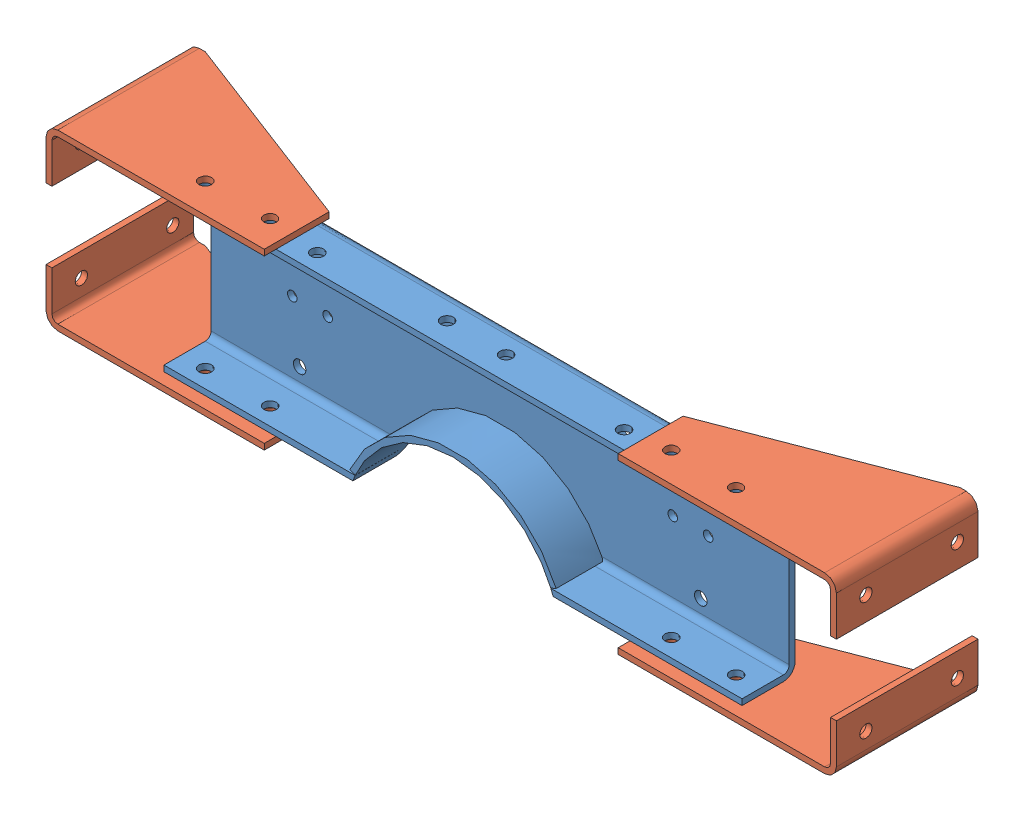
SolidWorks assembly SUB-1700-119, configuration Collapsed - No fasteners. Lengths in mm.
Overall size (850.9 213.23 152.4).
21 component instances, 4 part files, 54 mates.
Components (placement in the parent):
- 2526-CC2-1: 2526-CC2 [2526-CC2-001] at (0 0 -38.1)
- 2724-CC2-1: 2724-CC2 [Gusset-001] at (-419.1 87.3125 31.75) x (-1 0 0) z (0 0 -1)
- 2724-CC2-2: 2724-CC2 [Gusset-001] at (419.1 -87.3125 31.75) x (1 0 0) z (0 0 -1)
- 2724-CC2-3: 2724-CC2 [gusset-002] at (-419.1 -87.3125 31.75) x (-1 0 0) z (0 0 1)
- 2724-CC2-4: 2724-CC2 [gusset-002] at (419.1 87.3125 31.75)
- 08130XXXFH8Y-5: 08130XXXFH8Y [08130125FH8Y] at (-285.75 -93.6625 0) x (0.410138 0 -0.912023) z (0 -1 0) (hidden)
- 08130XXXFH8Y-6: 08130XXXFH8Y [08130125FH8Y] at (285.75 93.6625 0) x (-0.71256 0 -0.701612) z (0 1 0) (hidden)
- 08130XXXFH8Y-7: 08130XXXFH8Y [08130125FH8Y] at (-285.75 93.6625 0) x (-0.994905 0 0.100822) z (0 1 0) (hidden)
- 08130XXXFH8Y-8: 08130XXXFH8Y [08130125FH8Y] at (285.75 -93.6625 0) x (0.963893 0 -0.266289) z (0 -1 0) (hidden)
- 08130XXXFH8Y-1: 08130XXXFH8Y [08130125FH8Y] at (215.9 93.6625 0) x (0.260996 0 0.96534) z (0 1 0) (hidden)
- 08130XXXFH8Y-3: 08130XXXFH8Y [08130125FH8Y] at (-215.9 -93.6625 0) x (-0.084711 0 0.996406) z (0 -1 0) (hidden)
- 08130XXXFH8Y-2: 08130XXXFH8Y [08130125FH8Y] at (-215.9 93.6625 0) x (0.067732 0 0.997704) z (0 1 0) (hidden)
- 08130XXXFH8Y-4: 08130XXXFH8Y [08130125FH8Y] at (215.9 -93.6625 0) x (-0.215383 0 -0.97653) z (0 -1 0) (hidden)
- XXXXFLN8Y-2: XXXXFLN8Y [0813FLN8Y] at (-215.9 80.9625 0) x (0.067732 0 0.997704) z (0 -1 0) (hidden)
- XXXXFLN8Y-3: XXXXFLN8Y [0813FLN8Y] at (215.9 80.9625 0) x (0.299588 0 -0.954069) z (0 -1 0) (hidden)
- XXXXFLN8Y-8: XXXXFLN8Y [0813FLN8Y] at (-285.75 -80.9625 0) x (0.067732 0 0.997704) z (0 1 0) (hidden)
- XXXXFLN8Y-4: XXXXFLN8Y [0813FLN8Y] at (-215.9 -80.9625 0) x (0.067732 0 0.997704) z (0 1 0) (hidden)
- XXXXFLN8Y-5: XXXXFLN8Y [0813FLN8Y] at (285.75 80.9625 0) x (0.299588 0 -0.954069) z (0 -1 0) (hidden)
- XXXXFLN8Y-1: XXXXFLN8Y [0813FLN8Y] at (-285.75 80.9625 0) x (0.067732 0 0.997704) z (0 -1 0) (hidden)
- XXXXFLN8Y-7: XXXXFLN8Y [0813FLN8Y] at (215.9 -80.9625 0) x (-0.215383 0 -0.97653) z (0 1 0) (hidden)
- XXXXFLN8Y-6: XXXXFLN8Y [0813FLN8Y] at (285.75 -80.9625 0) x (0.299588 0 -0.954069) z (0 1 0) (hidden)
Mates (geometry in assembly coordinates):
- Distance1: distance = 38.1 mm aligned: plane of ?; plane of assembly
- Coincident2: coincident aligned: plane of ?; plane of assembly
- Coincident3: coincident aligned: plane of ?; plane of assembly
- Coincident5: coincident anti-aligned: plane of ?; plane of ?
- Coincident6: coincident anti-aligned: plane of ?; plane of ?
- Concentric5: concentric anti-aligned: cylinder of ?; cylinder of ?
- Concentric7: concentric aligned: cylinder of ?; cylinder of ?
- Concentric11: concentric aligned: cylinder of ?; cylinder of ?
- Concentric12: concentric aligned: cylinder of ?; cylinder of ?
- Coincident9: coincident anti-aligned: plane of ?; plane of ?
- Concentric15: concentric anti-aligned: cylinder of ?; cylinder of ?
- Coincident12: coincident anti-aligned: plane of ?; plane of ?
- Coincident13: coincident anti-aligned: plane of ?; plane of ?
- Concentric17: concentric anti-aligned: cylinder of ?; cylinder of ?
- Concentric18: concentric anti-aligned: cylinder of ?; cylinder of ?
- Coincident15: coincident anti-aligned: plane of ?; plane of ?
- Concentric19: concentric anti-aligned: cylinder of ?; cylinder of ?
- Concentric20: concentric anti-aligned: cylinder of ?; cylinder of ?
- Coincident16: coincident anti-aligned: plane of ?; plane of ?
- Coincident20: coincident anti-aligned: plane of ?; plane of ?
- Concentric25: concentric anti-aligned: cylinder of ?; cylinder of ?
- Coincident21: coincident anti-aligned: plane of ?; plane of ?
- Coincident22: coincident anti-aligned: plane of ?; plane of ?
- Coincident23: coincident anti-aligned: plane of ?; plane of ?
- Parallel3: parallel aligned: plane of ?; plane of ?
- Parallel5: parallel aligned: plane of ?; plane of ?
- Parallel6: parallel aligned: plane of ?; plane of ?
- Coincident24: coincident anti-aligned: plane of ?; plane of ?
- Parallel11: parallel aligned: plane of ?; plane of ?
- Parallel13: parallel aligned: plane of ?; plane of ?
- Parallel14: parallel aligned: plane of ?; plane of ?
- Coincident25: coincident aligned: plane of ?; plane of ?
- Coincident26: coincident aligned: plane of ?; plane of ?
- Coincident27: coincident aligned: plane of ?; plane of ?
- Coincident28: coincident anti-aligned: plane of ?; plane of ?
- Concentric27: concentric aligned: cylinder of ?; cylinder of ?
- Concentric28: concentric anti-aligned: circle of ?; cylinder of ?
- Concentric31: concentric aligned: cylinder of ?; cylinder of ?
- Coincident30: coincident anti-aligned: plane of ?; plane of ?
- Coincident31: coincident aligned: plane of ?; plane of ?
- Concentric32: concentric aligned: cylinder of ?; cylinder of ?
- Coincident32: coincident anti-aligned: plane of ?; plane of ?
- Concentric33: concentric anti-aligned: circle of ?; cylinder of ?
- Coincident33: coincident anti-aligned: plane of ?; plane of ?
- Concentric34: concentric aligned: cylinder of ?; cylinder of ?
- Coincident34: coincident anti-aligned: plane of ?; plane of ?
- Concentric35: concentric aligned: cylinder of ?; cylinder of ?
- Coincident35: coincident anti-aligned: plane of ?; plane of ?
- Concentric36: concentric anti-aligned: cylinder of ?; cylinder of ?
- Concentric39: concentric anti-aligned: cylinder of ?; cylinder of ?
- Concentric40: concentric anti-aligned: cylinder of ?; cylinder of ?
- Coincident36: coincident anti-aligned: plane of ?; plane of ?
- Concentric42: concentric anti-aligned: cylinder of ?; cylinder of ?
- Coincident37: coincident anti-aligned: 
